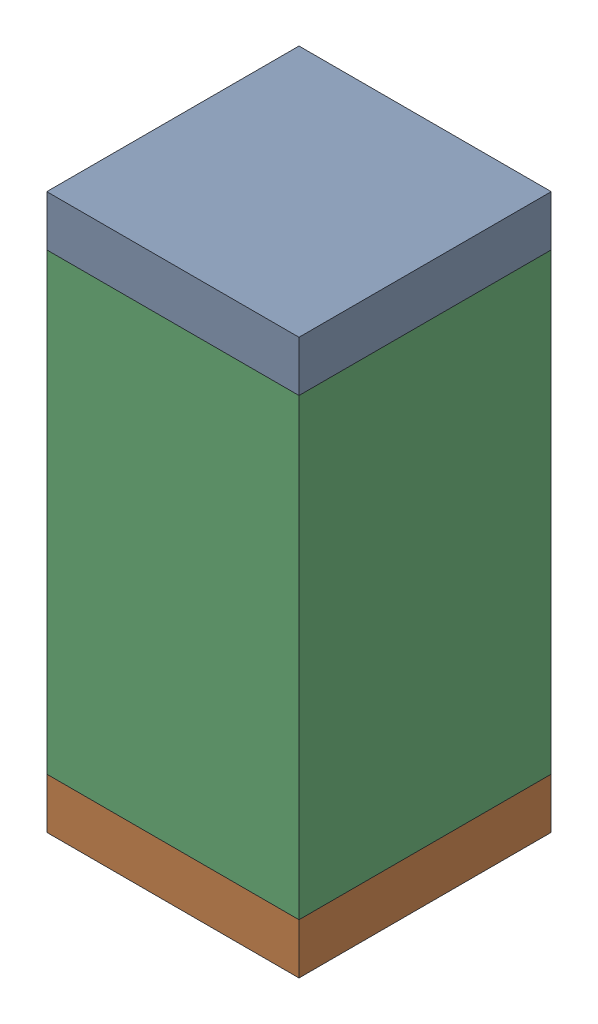
SolidWorks assembly C19, configuration Default. Lengths in mm.
Overall size (0.5 1.1 0.5).
6 component instances, 2 part files, 0 mates.
Components (placement in the parent):
- 810157360-1: 810157360 [Default] at (134.5 17.35 0) size (0.5 0.1 0.5)
  - Extruded_9-1: Extruded_9 [Default] at origin size (0.5 0.1 0.5)
- 810157360-2: 810157360 [Default] at (134.5 16.35 0) size (0.5 0.1 0.5)
  - Extruded_9-1: Extruded_9 [Default] at origin size (0.5 0.1 0.5)
- 791586336-1: 791586336 [Default] at (134.5 16.85 0) size (0.5 0.9 0.5)
  - Extruded_8-1: Extruded_8 [Default] at origin size (0.5 0.9 0.5)
